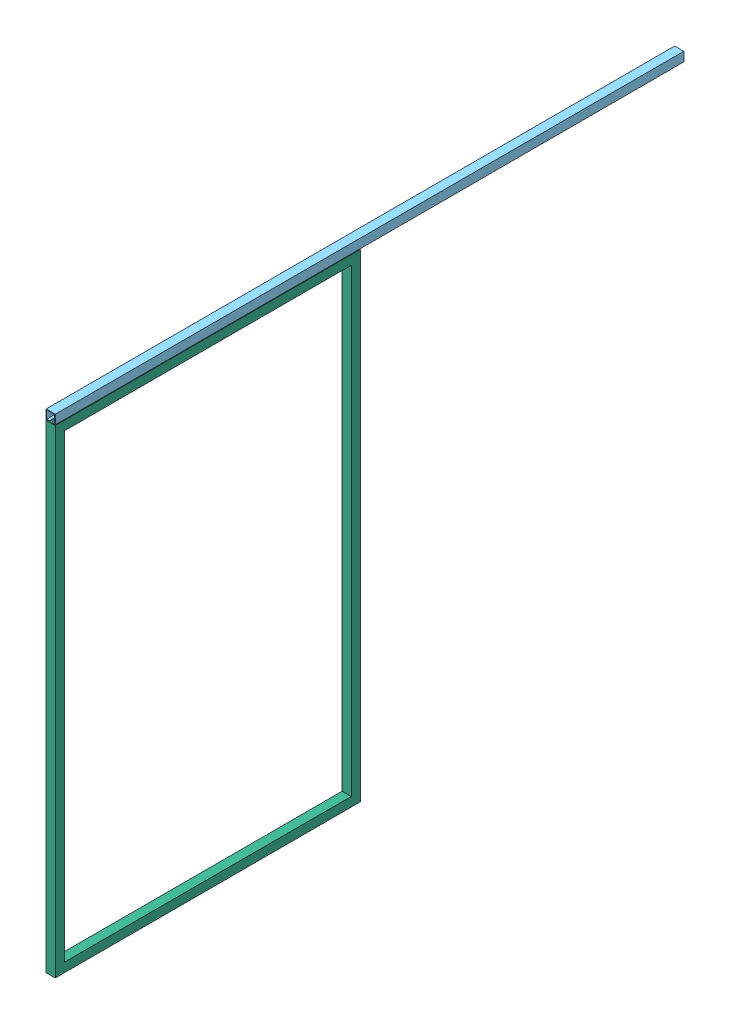
SolidWorks assembly FullDoorWithBar, configuration Default. Lengths in mm.
Overall size (30 1600 2060).
32 component instances, 9 part files, 19 mates.
Components (placement in the parent):
- FullCar-1: FullCar [Default] at (0 -6.25 870) size (25 18.99 35)
  - Carriage-1: Carriage [Default] at origin size (24.16 8.5 35)
  - LockWheels-1: LockWheels [Default] at (12.5 0 7.5) x (0 0.86398 0.503526) z (0 -0.503526 0.86398) size (3.5 7.63 3.5)
  - LockWheels-2: LockWheels [Default] at (12.5 0 -7.5) x (0 -0.86398 0.503526) z (0 -0.503526 -0.86398) size (3.5 7.63 3.5)
  - LockWheels-3: LockWheels [Default] at (-12.5 0 7.5) x (0 -0.86398 -0.503526) z (0 -0.503526 0.86398) size (3.5 7.63 3.5)
  - LockWheels-4: LockWheels [Default] at (-12.5 0 -7.5) x (0 0.86398 -0.503526) z (0 -0.503526 -0.86398) size (3.5 7.63 3.5)
  - WheelCarriage-1: WheelCarriage [Default] at (9.25 0 7.5) x (0 -0.862763 -0.505608) z (1 0 0) size (13.5 13.5 3.5)
  - WheelCarriage-2: WheelCarriage [Default] at (9.25 0 -7.5) x (0 -0.862763 0.505608) z (-1 0 0) size (13.5 13.5 3.5)
  - WheelCarriage-3: WheelCarriage [Default] at (-9.25 0 7.5) x (0 -0.862763 -0.505608) z (1 0 0) size (13.5 13.5 3.5)
  - WheelCarriage-4: WheelCarriage [Default] at (-9.25 0 -7.5) x (0 -0.862763 0.505608) z (-1 0 0) size (13.5 13.5 3.5)
  - Support-1: Support [Default] at (0 -7.5 0) x (0 0 1) z (-1 0 0) size (13 7.5 7)
- FrontHorizontalBar-1: FrontHorizontalBar [Default] at origin size (30 30 2060)
- Door-1: Door [Default] at (0 -801.125 530) x (0 0 1) z (-1 0 0) size (1000 1572.75 30)
- Lid_Locker-1: Lid_Locker [Default] at (-3.725 -13.75 870) x (0 0 1) z (-1 0 0) size (13.9 5.5 1.7)
- FullCar-4: FullCar [Default] at (0 -6.25 190) size (25 18.99 35)
  - Carriage-1: Carriage [Default] at origin size (24.16 8.5 35)
  - LockWheels-1: LockWheels [Default] at (12.5 0 7.5) x (0 0.86398 0.503526) z (0 -0.503526 0.86398) size (3.5 7.63 3.5)
  - LockWheels-2: LockWheels [Default] at (12.5 0 -7.5) x (0 -0.86398 0.503526) z (0 -0.503526 -0.86398) size (3.5 7.63 3.5)
  - LockWheels-3: LockWheels [Default] at (-12.5 0 7.5) x (0 -0.86398 -0.503526) z (0 -0.503526 0.86398) size (3.5 7.63 3.5)
  - LockWheels-4: LockWheels [Default] at (-12.5 0 -7.5) x (0 0.86398 -0.503526) z (0 -0.503526 -0.86398) size (3.5 7.63 3.5)
  - WheelCarriage-1: WheelCarriage [Default] at (9.25 0 7.5) x (0 -0.862763 -0.505608) z (1 0 0) size (13.5 13.5 3.5)
  - WheelCarriage-2: WheelCarriage [Default] at (9.25 0 -7.5) x (0 -0.862763 0.505608) z (-1 0 0) size (13.5 13.5 3.5)
  - WheelCarriage-3: WheelCarriage [Default] at (-9.25 0 7.5) x (0 -0.862763 -0.505608) z (1 0 0) size (13.5 13.5 3.5)
  - WheelCarriage-4: WheelCarriage [Default] at (-9.25 0 -7.5) x (0 -0.862763 0.505608) z (-1 0 0) size (13.5 13.5 3.5)
  - Support-1: Support [Default] at (0 -7.5 0) x (0 0 1) z (-1 0 0) size (13 7.5 7)
- Lid_Locker-2: Lid_Locker [Default] at (-3.725 -13.75 190) x (0 0 1) z (-1 0 0) size (13.9 5.5 1.7)
- Full_Restrictor-1: Full_Restrictor [Default] at (0 -12.75 897.6) x (-1 0 0) z (0 0 -1) size (25 10.16 20.1)
  - Lid_Restrictor-1: Lid_Restrictor [Default] at (0 8.5 10.1) x (1 0 0) z (0 0 -1) size (2.81 2.81 3)
  - Restrictor-1: Restrictor [Default] at origin size (25 9.5 19.9)
- Full_Restrictor-2: Full_Restrictor [Default] at (0 -12.75 -897.6) size (25 10.16 20.1)
  - Lid_Restrictor-1: Lid_Restrictor [Default] at (0 8.5 10.1) x (1 0 0) z (0 0 -1) size (2.81 2.81 3)
  - Restrictor-1: Restrictor [Default] at origin size (25 9.5 19.9)
Mates (geometry in assembly coordinates):
- Coincident1: coincident aligned: plane of FrontHorizontalBar-1 through (0 0 0) normal (0 0 1)
- Coincident2: coincident aligned: plane of FrontHorizontalBar-1 through (0 0 0) normal (1 0 0)
- Coincident3: coincident aligned: plane of FrontHorizontalBar-1 through (0 0 0) normal (0 1 0)
- Coincident4: coincident aligned: plane of FullCar-1 through (0 -6.25 870) normal (1 0 0)
- Tangent1: tangent anti-aligned: cylinder of FullCar-1/WheelCarriage-3 through (-7.5 -6.25 877.5) axis (-1 0 0) radius 6.75; plane of FrontHorizontalBar-1 through (-13 -13 1030) normal (0 1 0)
- Tangent2: tangent anti-aligned: cylinder of FullCar-1/WheelCarriage-1 through (11 -6.25 877.5) axis (-1 0 0) radius 6.75; plane of FrontHorizontalBar-1 through (4 -13 1030) normal (0 1 0)
- Tangent3: tangent anti-aligned: cylinder of FullCar-1/WheelCarriage-4 through (-11 -6.25 862.5) axis (1 0 0) radius 6.75; plane of FrontHorizontalBar-1 through (-13 -13 1030) normal (0 1 0)
- Tangent4: tangent anti-aligned: cylinder of FullCar-1/WheelCarriage-2 through (7.5 -6.25 862.5) axis (1 0 0) radius 6.75; plane of FrontHorizontalBar-1 through (4 -13 1030) normal (0 1 0)
- Coincident5: coincident anti-aligned: plane of Door-1 through (0 -801.125 530) normal (-1 0 0)
- Coincident6: coincident anti-aligned: plane of FullCar-1/Support-1 through (-3.5 -12.25 870) normal (0 -1 0); plane of Door-1 through (0 -12.25 875) normal (0 1 0)
- Coincident8: coincident aligned: plane of FullCar-1/Support-1 through (0 -13.75 870) normal (0 0 1); plane of Door-1 through (-15 -12.25 870) normal (0 0 1)
- Parallel1: parallel anti-aligned: plane of FullCar-1/Carriage-1 through (0 -6.25 870) normal (1 0 0); plane of Lid_Locker-1 through (-3.725 -13.75 870) normal (-1 0 0)
- Coincident11: coincident anti-aligned: plane of FullCar-1/Support-1 through (-3.5 -13.75 870) normal (-1 0 0); plane of Lid_Locker-1 through (-3.5 -13.75 870) normal (1 0 0)
- Coincident12: coincident anti-aligned: plane of FullCar-1/Support-1 through (-3.5 -11.5 870) normal (0 1 0); plane of Lid_Locker-1 through (-2.25 -11.5 870) normal (0 -1 0)
- Coincident13: coincident aligned: plane of FullCar-1/Support-1 through (0 -13.75 870) normal (0 0 1); plane of Lid_Locker-1 through (-3.725 -13.75 870) normal (0 0 1)
- Coincident15: coincident anti-aligned: plane of FrontHorizontalBar-1 through (-13 -13 1030) normal (0 1 0); plane of Full_Restrictor-1/Restrictor-1 through (0 -13 897.6) normal (0 -1 0)
- Coincident16: coincident anti-aligned: plane of FrontHorizontalBar-1 through (0 0 0) normal (1 0 0); plane of Full_Restrictor-1/Restrictor-1 through (0 -12.75 897.6) normal (-1 0 0)
- Distance1: distance = 122.4 mm aligned: plane of Full_Restrictor-1/Restrictor-1 through (12.5 -12.5 907.6) normal (0 0 1); plane of FrontHorizontalBar-1 through (0 0 1030) normal (0 0 1)
- LimitDistance1: limit distance = 1060 mm aligned: plane of Door-1 through (-15 -17.25 30) normal (0 0 -1); plane of FrontHorizontalBar-1 through (0 0 -1030) normal (0 0 -1)
